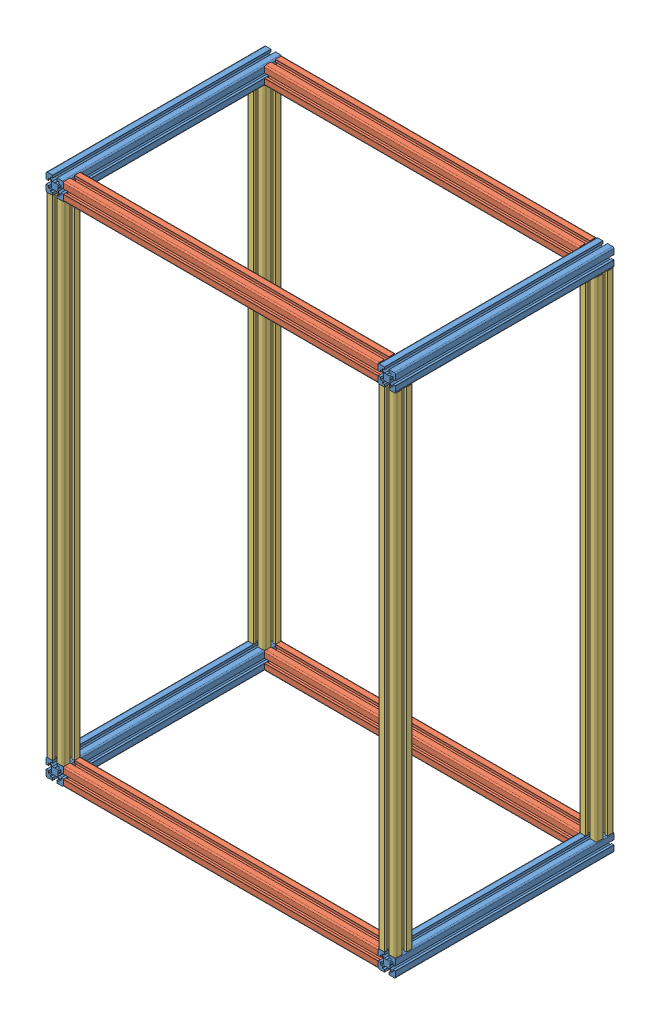
SolidWorks assembly Assem6, configuration ﾃﾞﾌｫﾙﾄ. Lengths in mm.
Overall size (800 1200 500).
12 component instances, 3 part files, 11 mates.
Components (placement in the parent):
- Flame_500mm-1: Flame_500mm [ﾃﾞﾌｫﾙﾄ] at origin size (40 40 500)
- Flame_500mm-2: Flame_500mm [ﾃﾞﾌｫﾙﾄ] at (760 0 0) size (40 40 500)
- Flame_720mm-1: Flame_720mm [ﾃﾞﾌｫﾙﾄ] at (70 100 30) x (0 0 -1) z (-1 0 0) size (40 40 720)
- Flame_720mm-2: Flame_720mm [ﾃﾞﾌｫﾙﾄ] at (790 0 -430) x (0 0 -1) z (1 0 0) size (40 40 720)
- Flame_1120mm-1: Flame_1120mm [ﾃﾞﾌｫﾙﾄ] at (100 70 -70) x (0 0 1) z (0 -1 0) size (40 40 1120)
- Flame_1120mm-2: Flame_1120mm [ﾃﾞﾌｫﾙﾄ] at (0 70 -530) x (1 0 0) z (0 -1 0) size (40 40 1120)
- Flame_1120mm-3: Flame_1120mm [ﾃﾞﾌｫﾙﾄ] at (760 70 -530) x (1 0 0) z (0 -1 0) size (40 40 1120)
- Flame_1120mm-4: Flame_1120mm [ﾃﾞﾌｫﾙﾄ] at (760 70 -70) x (1 0 0) z (0 -1 0) size (40 40 1120)
- Flame_500mm-3: Flame_500mm [ﾃﾞﾌｫﾙﾄ] at (0 1160 0) size (40 40 500)
- Flame_500mm-4: Flame_500mm [ﾃﾞﾌｫﾙﾄ] at (760 1160 0) size (40 40 500)
- Flame_720mm-3: Flame_720mm [ﾃﾞﾌｫﾙﾄ] at (790 1160 -430) x (0 0 -1) z (1 0 0) size (40 40 720)
- Flame_720mm-4: Flame_720mm [ﾃﾞﾌｫﾙﾄ] at (790 1160 30) x (0 0 -1) z (1 0 0) size (40 40 720)
Mates (geometry in assembly coordinates):
- 一致1: coincident aligned: line of Flame_500mm-1 through (11.7 70 67) axis (0 0 -1); line of Flame_720mm-1 through (70 67 0) axis (0 -1 0)
- 一致2: coincident: point of Flame_500mm-2; unknown of Flame_720mm-1
- 一致3: coincident: unknown of Flame_500mm-1; unknown of Flame_720mm-2
- 一致4: coincident: unknown of Flame_500mm-1; unknown of Flame_1120mm-1
- 一致6: coincident: unknown of Flame_500mm-1; unknown of Flame_1120mm-2
- 一致7: coincident: unknown of Flame_500mm-2; unknown of Flame_1120mm-3
- 一致8: coincident: unknown of Flame_500mm-2; unknown of Flame_1120mm-4
- 一致10: coincident: unknown of Flame_1120mm-2; unknown of Flame_500mm-3
- 一致11: coincident: unknown of Flame_1120mm-4; unknown of Flame_500mm-4
- 一致14: coincident: unknown of Flame_500mm-4; unknown of Flame_720mm-4
- 一致16: coincident: unknown of Flame_500mm-4; unknown of Flame_720mm-3
